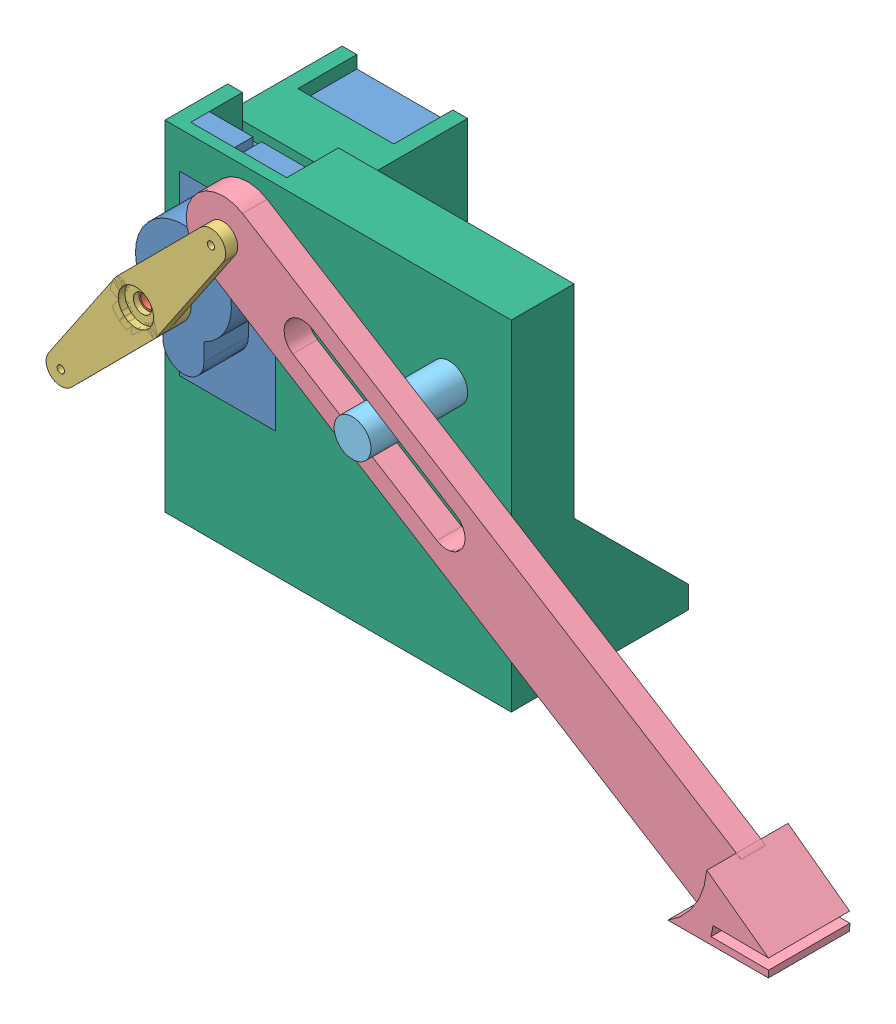
SolidWorks assembly 舵机装配, configuration 默认. Lengths in mm.
Overall size (103.68 58.84 38.8).
6 component instances, 6 part files, 16 mates.
Components (placement in the parent):
- 舵机-2: 舵机 [默认] at (6.5 6.5 -6) x (0 -1 0) z (0 0 -1) size (34 13 30)
- 舵机齿轮-2: 舵机齿轮 [默认] at (0 0 0.3) x (0.999998 -0.001941 0) z (0 0 1) size (4.97 4.97 8.8)
- 摇臂-2: 摇臂 [默认] at (0 0 6.94) x (-0.635619 -0.772003 0) z (0 0 -1) size (36 7 4)
- 连接杆-1: 连接杆 [默认] at (18.9028 -0.1159 3.4) x (0.849193 -0.528082 0) z (0 0 1) size (95.35 10 11)
- 支点-2: 支点 [默认] at (30.0391 0.0232 -9) x (0.865492 0.500923 0) z (0 0 1) size (5 5 16.11)
- 舵机固定外壳-1: 舵机固定外壳 [默认] at (6.5 6.5 -7.5) x (0 1 0) z (0 0 1) size (46 46.92 24)
Mates (geometry in assembly coordinates):
- 重合3: coincident: point of 舵机-2; point of assembly
- 重合17: coincident aligned: plane of 舵机-2 through (0 -8.2658 0) normal (0 0 1)
- 重合14: coincident anti-aligned: plane of 舵机-2 through (0 0 -4) normal (0 0 1); plane of 舵机齿轮-2 through (0 0 -4) normal (0 0 -1)
- 同心4: concentric aligned: circle of 舵机-2; circle of 舵机齿轮-2
- 重合16: coincident anti-aligned: plane of 舵机齿轮-2 through (0 0 4.8) normal (0 0 1); plane of 摇臂-2 through (-10.1699 -12.352 4.8) normal (0 0 -1)
- 同心5: concentric aligned: circle of 舵机齿轮-2; circle of 摇臂-2
- 同心6: concentric aligned: circle of 摇臂-2; circle of 连接杆-1
- 重合21: coincident anti-aligned: plane of 摇臂-2 through (-10.1699 -12.352 4.8) normal (0 0 -1); plane of 连接杆-1 through (10.1699 12.352 4.8) normal (0 0 1)
- 距离1: distance = 0.001 mm anti-aligned: cylinder of 支点-2 through (30.0227 0.0064 7.1127) axis (0 0 -1) radius 2.5; plane of 连接杆-1 through (39.1458 -8.611 1.465) normal (0.528082 0.849193 0)
- 重合22: coincident anti-aligned: plane of 舵机-2 through (6.5 6.5 -30) normal (1 0 0); plane of 舵机固定外壳-1 through (6.5 6.5 -6) normal (-1 0 0)
- 重合23: coincident anti-aligned: plane of 舵机-2 through (6.5 6.5 -30) normal (0 1 0); plane of 舵机固定外壳-1 through (6.5 6.5 -30) normal (0 -1 0)
- 重合24: coincident anti-aligned: plane of 舵机-2 through (6.5 6.5 -7.5) normal (0 0 1); plane of 舵机固定外壳-1 through (6.5 6.5 -7.5) normal (0 0 -1)
- 平行3: parallel aligned: plane of 舵机固定外壳-1 through (6.5 6.5 -7.5) normal (0 1 0)
- 同心11: concentric anti-aligned: cylinder of 支点-2 through (30.0227 0.0064 7.1127) axis (0 0 -1) radius 2.5; cylinder of 舵机固定外壳-1 through (30.0227 0.0064 -30.001) axis (0 0 1) radius 2.5
- 重合25: coincident aligned: plane of 支点-2 through (30.0227 0.0064 -9) normal (0 0 -1); plane of 舵机固定外壳-1 through (6.5 6.5 -9) normal (0 0 -1)
- 相切1: tangent anti-aligned: plane of 连接杆-1 through (41.7862 -4.365 1.465) normal (-0.528082 -0.849193 0); cylinder of 支点-2 through (30.0227 0.0064 7.1127) axis (0 0 -1) radius 2.5
